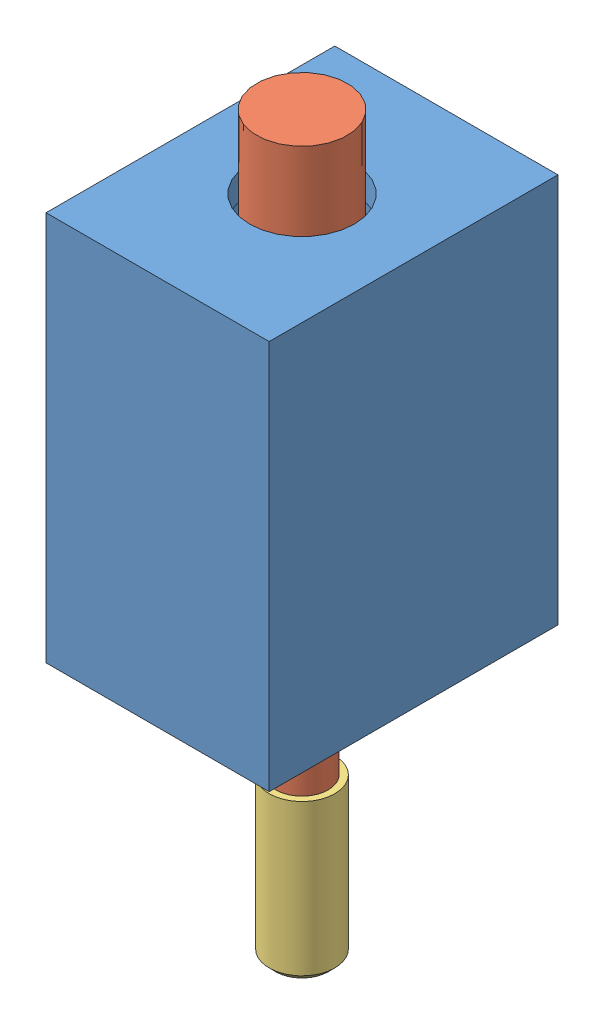
SolidWorks assembly Assem1, configuration Default. Lengths in mm.
Overall size (17 55.9 22).
3 component instances, 3 part files, 4 mates.
Components (placement in the parent):
- Solenoid_Mount-2: Solenoid_Mount [Default] at (6.5641 46.5695 46.2525) x (1 0 0) z (0 0 -1) size (17 29.7 22)
- Solenoid_Shaft-1: Solenoid_Shaft [Default] at (15.0641 0.2373 35.2525) x (-0.773677 0 0.63358) z (-0.63358 0 -0.773677) size (6.9 51.9 6.9)
- Solenoid_Cap-1: Solenoid_Cap [Default] at (15.0641 -3.7627 35.2525) x (0.200587 0 -0.979676) z (0.979676 0 0.200587) size (5 12 5)
Mates (geometry in assembly coordinates):
- Concentric1: concentric anti-aligned: cylinder of Solenoid_Mount-2 through (15.0641 46.5695 35.2525) axis (0 -1 0) radius 2; cylinder of Solenoid_Shaft-1 through (15.0641 8.6898 35.2525) axis (0 1 0) radius 2
- Coincident1: coincident aligned: plane of Solenoid_Mount-2 through (6.5641 16.8695 24.2525) normal (0 -1 0); plane of Solenoid_Shaft-1 through (13.0622 16.8695 36.8919) normal (0 -1 0)
- Concentric2: concentric aligned: cylinder of Solenoid_Shaft-1 through (15.0641 8.6898 35.2525) axis (0 1 0) radius 2; cylinder of Solenoid_Cap-1 through (15.0641 -20.9942 35.2525) axis (0 1 0) radius 2
- Coincident2: coincident anti-aligned: plane of Solenoid_Shaft-1 through (15.0641 0.2373 35.2525) normal (0 -1 0); plane of Solenoid_Cap-1 through (15.0641 0.2373 35.2525) normal (0 1 0)
